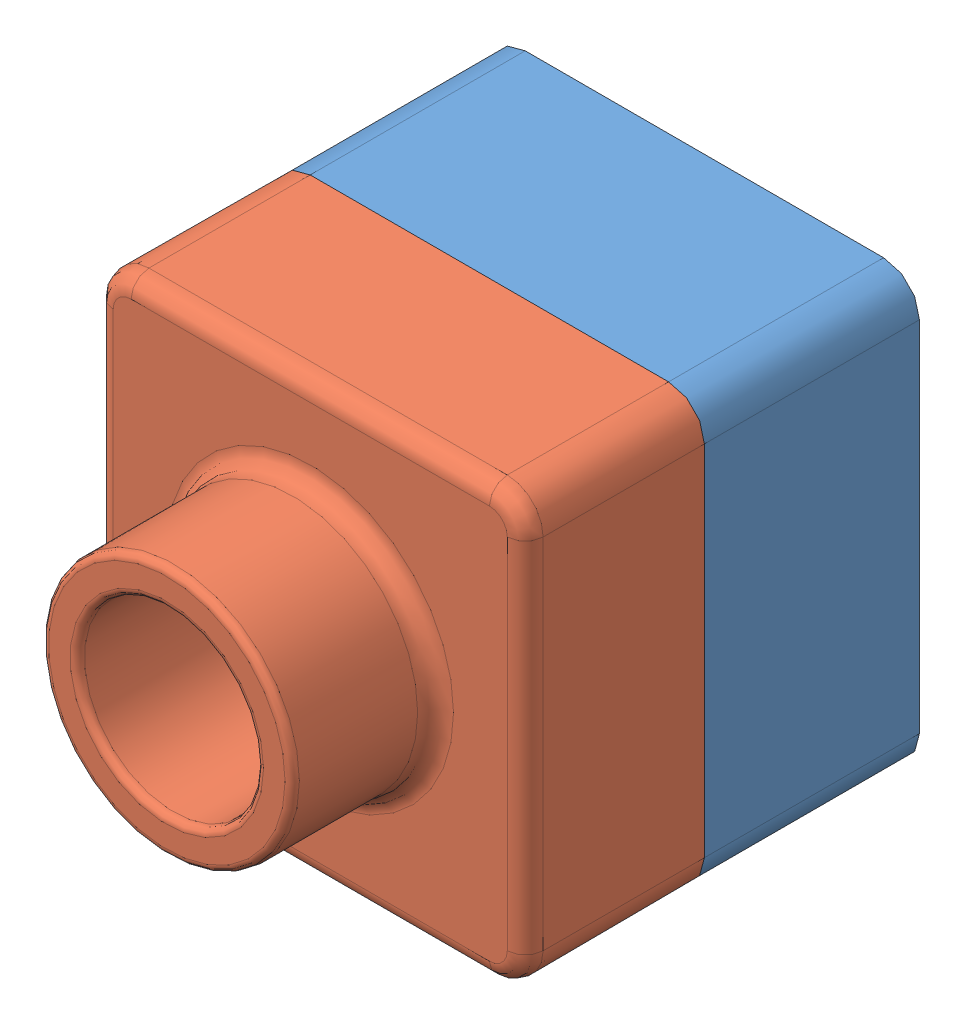
SolidWorks assembly sestava_krabicky, configuration Výchozí. Lengths in mm.
Overall size (120 120 150).
2 component instances, 2 part files, 3 mates.
Components (placement in the parent):
- krabicka2-1: krabicka2 [Výchozí] at (21.2672 10.4474 -31.7129) size (120 120 90)
- krabicka1-1: krabicka1 [Výchozí] at (21.2672 130.4474 28.2871) size (120 120 90)
Mates (geometry in assembly coordinates):
- Sjednocená1: coincident: plane of krabicka2-1; plane of krabicka1-1
- Sjednocená2: coincident: plane of krabicka2-1; plane of krabicka1-1
- Sjednocená3: coincident anti-aligned: plane of krabicka2-1; plane of krabicka1-1
